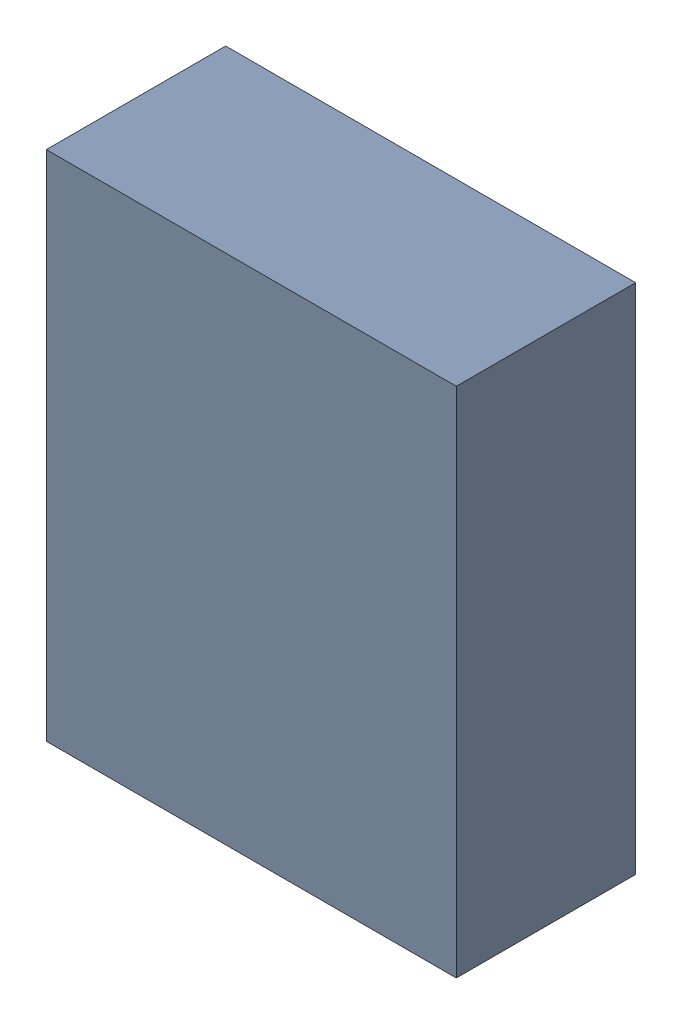
SolidWorks assembly Q2_1, configuration Default. Lengths in mm.
Overall size (4 5 1.75).
2 component instances, 1 part files, 0 mates.
Components (placement in the parent):
- 76846376-1: 76846376 [Default] at (6.858 19.5834 -2.1615) size (4 5 1.75)
  - Extruded-1: Extruded [Default] at origin size (4 5 1.75)
